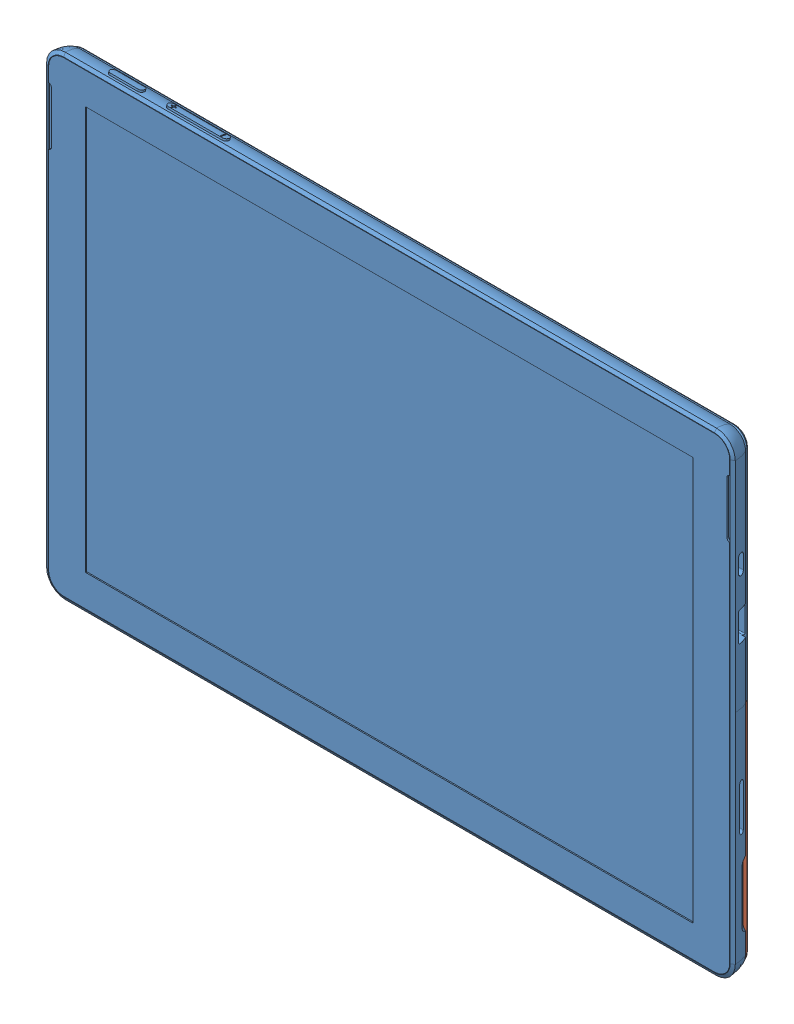
SolidWorks assembly Assemblage SP7, configuration Défaut. Lengths in mm.
Overall size (292.34 201.84 8.54).
2 component instances, 2 part files, 2 mates.
Components (placement in the parent):
- Surface pro 7-1: Surface pro 7 [Défaut] at (-5.3118 5.3661 293.3355) size (292.34 201.84 8.54)
- kickstand SP7-1: kickstand SP7 [Défaut] at (3.1393 5.1661 293.3355) size (288.24 98.42 2.1)
Mates (geometry in assembly coordinates):
- Distance2: distance = 0.2 mm anti-aligned: plane of kickstand SP7-1 through (140.6882 5.1661 295.3355) normal (0 1 0); plane of Surface pro 7-1 through (-149.0193 5.3661 293.7159) normal (0 -1 0)
- Coïncidente6: coincident aligned: plane of Surface pro 7-1 through (-5.3118 5.3661 293.3355) normal (0 0 -1); plane of kickstand SP7-1 through (-143.3118 -87.1339 293.3355) normal (0 0 -1)
